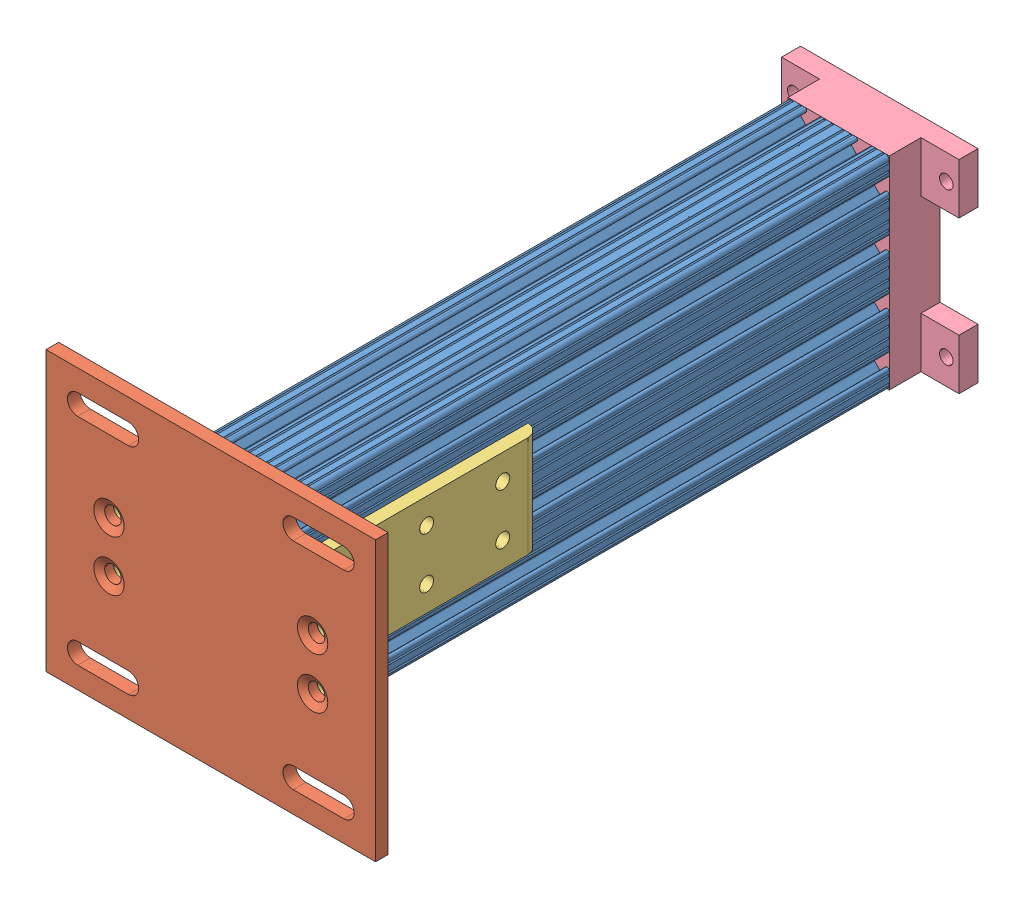
SolidWorks assembly breadboard support leg assembly, configuration Default. Lengths in mm.
Overall size (165.1 139.7 339.72).
6 component instances, 4 part files, 6 mates.
Components (placement in the parent):
- 8020-2040 leg for breadboard support-1: 8020-2040 leg for breadboard support [Default] at (-48.9055 -77.0614 78.1612) size (50.8 101.6 307.98)
- 8020-2387-DEFAULT-1: 8020-2387-DEFAULT [Default] at (-34.9863 -22.6888 91.8816) x (0 1 0) z (-1 0 0) size (139.7 133.35 165.1)
  - 8020-2387-DEFAULT_238708-1: 8020-2387-DEFAULT_238708 [Default] at (-67.1549 7.3704 27.8119) size (139.7 6.35 165.1)
  - 8020-2387-DEFAULT_238509-1: 8020-2387-DEFAULT_238509 [Default] at (9.1264 0.0214 49.7635) x (0 0 1) z (-1 0 0) size (50.8 127 50.8)
  - 8020-2387-DEFAULT_238509-2: 8020-2387-DEFAULT_238509 [Default] at (-41.6736 0.0214 -46.9187) x (0 0 -1) z (1 0 0) size (50.8 127 50.8)
- breadboard support leg top bracket-1: breadboard support leg top bracket [Default] at (-61.6055 -89.7614 -229.8138) x (0 1 0) z (-1 0 0) size (101.6 25.4 88.9)
Mates (geometry in assembly coordinates):
- Coincident1: coincident anti-aligned: plane of 8020-2040 leg for breadboard support-1 through (-61.6055 -36.3198 78.1612) normal (0 0 1); plane of 8020-2387-DEFAULT-1/8020-2387-DEFAULT_238708-1 through (-36.4088 -207.3239 78.1612) normal (0 0 -1)
- Coincident2: coincident anti-aligned: plane of 8020-2040 leg for breadboard support-1 through (-10.8056 -41.095 -229.8138) normal (1 0 0); plane of 8020-2387-DEFAULT-1/8020-2387-DEFAULT_238509-2 through (-10.8056 -13.5624 150.9329) normal (-1 0 0)
- Distance1: distance = 19.05 mm aligned: plane of 8020-2387-DEFAULT-1/8020-2387-DEFAULT_238708-1 through (-36.4088 -108.8114 78.1612) normal (0 -1 0); plane of 8020-2040 leg for breadboard support-1 through (-38.3391 -89.7614 -229.8138) normal (0 -1 0)
- Coincident3: coincident anti-aligned: plane of 8020-2040 leg for breadboard support-1 through (-61.6055 -36.3198 -229.8138) normal (0 0 -1); plane of breadboard support leg top bracket-1 through (-10.8055 -89.7614 -229.8138) normal (0 0 1)
- Concentric1: concentric anti-aligned: circle of 8020-2040 leg for breadboard support-1; circle of breadboard support leg top bracket-1
- Concentric2: concentric anti-aligned: circle of 8020-2040 leg for breadboard support-1; circle of breadboard support leg top bracket-1
